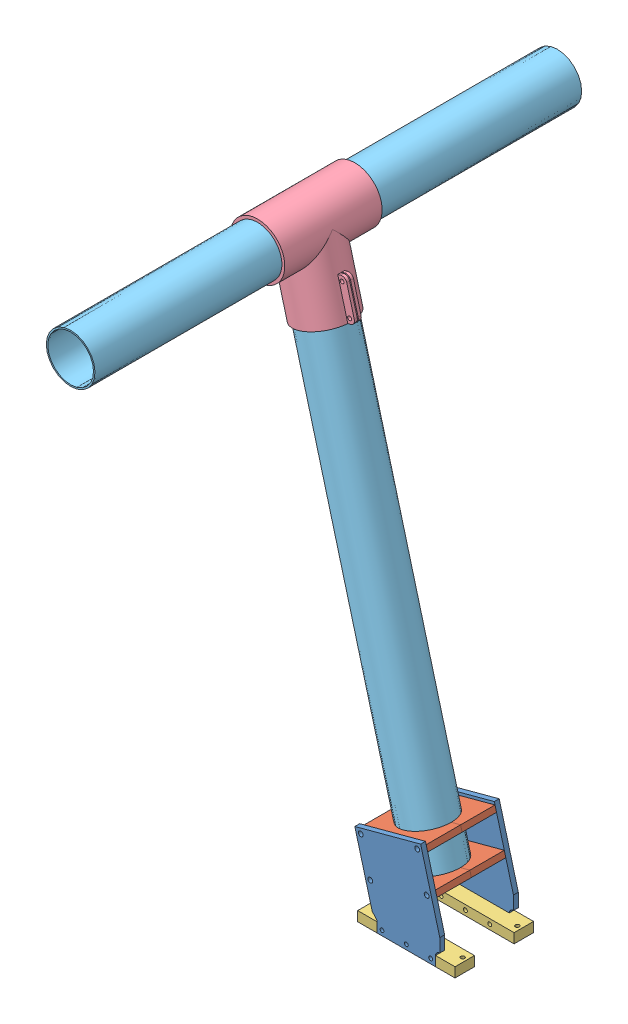
SolidWorks assembly DroneLegAssembly, configuration Default. Lengths in mm.
Overall size (228.54 591.89 500).
11 component instances, 5 part files, 25 mates.
Components (placement in the parent):
- DroneLegHolder-1: DroneLegHolder [Default] at (24.5531 1.0156 69.8023) size (87.27 101.47 5)
- 50mmTubeClamp-1: 50mmTubeClamp [Default] at (47.7584 47.4978 110.1489) x (0.965926 0.258819 0) z (-0.258819 0.965926 0) size (70 35.35 6)
- 50mmTubeClamp-2: 50mmTubeClamp [Default] at (35.6425 92.7146 110.1489) x (-0.965926 -0.258819 0) z (0.258819 -0.965926 0) size (70 35.35 6)
- 50mmTubeClamp-3: 50mmTubeClamp [Default] at (35.6425 92.7146 110.1489) x (0.965926 0.258819 0) z (0.258819 -0.965926 0) size (70 35.35 6)
- 50mmTubeClamp-4: 50mmTubeClamp [Default] at (45.1702 57.157 110.1489) x (0.965926 0.258819 0) z (0.258819 -0.965926 0) size (70 35.35 6)
- DroneLegHolder-2: DroneLegHolder [Default] at (24.5531 1.0156 145.4956) size (87.27 101.47 5)
- 50mmDroneLegToBase-1: 50mmDroneLegToBase [Default] at (47.7381 1.0156 73.7515) x (0 0 1) z (-1 0 0) size (20 10 100)
- 50mmDroneLegToBase-2: 50mmDroneLegToBase [Default] at (61.3681 1.0156 146.5463) x (0 0 -1) z (1 0 0) size (20 10 100)
- New50mmBottomJoint-1: New50mmBottomJoint [Default] at (-88.6393 556.5407 160.1489) x (0.965926 0.258819 0) z (0 0 -1) size (64 103 100)
- Short50mmDroneLeg-1: Short50mmDroneLeg [Default] at (47.2407 49.4296 110.1489) x (0.779439 0.20885 -0.590641) z (-0.258819 0.965926 0) size (50 50 500)
- Short50mmDroneLeg-2: Short50mmDroneLeg [Default] at (-88.6393 556.5407 -147.8451) x (0.716049 -0.69805 0) z (0 0 1) size (50 50 500)
Mates (geometry in assembly coordinates):
- Coincident1: coincident anti-aligned: plane of 50mmTubeClamp-2 through (4.4233 73.9967 110.1489) normal (0 0 1); plane of 50mmTubeClamp-3 through (72.0381 92.1141 110.1489) normal (0 0 -1)
- Coincident3: coincident anti-aligned: plane of 50mmTubeClamp-1 through (21.022 50.6865 110.1489) normal (0 0 1); plane of 50mmTubeClamp-4 through (23.6102 41.0273 110.1489) normal (0 0 -1)
- Coincident5: coincident anti-aligned: plane of 50mmTubeClamp-4 through (81.5658 56.5564 145.4956) normal (0 0 1); plane of DroneLegHolder-2 through (88.9139 11.0156 145.4956) normal (0 0 -1)
- Coincident6: coincident anti-aligned: plane of DroneLegHolder-2 through (88.9139 11.0156 145.4956) normal (0 0 -1); plane of 50mmDroneLegToBase-2 through (84.5531 11.0156 145.4956) normal (0 0 1)
- Coincident9: coincident anti-aligned: plane of DroneLegHolder-2 through (24.5531 11.0156 155.4956) normal (-1 0 0); plane of 50mmDroneLegToBase-2 through (24.5531 11.0156 155.4956) normal (1 0 0)
- Concentric13: concentric anti-aligned: cylinder of DroneLegHolder-2 through (29.5531 6.0156 155.4956) axis (0 0 -1) radius 2; cylinder of 50mmDroneLegToBase-2 through (29.5531 6.0156 115.4956) axis (0 0 1) radius 2
- Concentric14: concentric aligned: cylinder of DroneLegHolder-1 through (29.5531 6.0156 79.8023) axis (0 0 -1) radius 2; cylinder of 50mmDroneLegToBase-1 through (29.5531 6.0156 104.8023) axis (0 0 -1) radius 2
- Concentric41: concentric anti-aligned: cylinder of 50mmTubeClamp-2 through (38.2307 83.0554 110.1489) axis (-0.258819 0.965926 0) radius 25; cylinder of Short50mmDroneLeg-1 through (-82.1688 532.3925 110.1489) axis (0.258819 -0.965926 0) radius 25
- Concentric42: concentric anti-aligned: cylinder of New50mmBottomJoint-1 through (-69.2278 484.0962 110.1489) axis (-0.258819 0.965926 0) radius 25; cylinder of Short50mmDroneLeg-1 through (-82.1688 532.3925 110.1489) axis (0.258819 -0.965926 0) radius 25
- Concentric43: concentric anti-aligned: cylinder of New50mmBottomJoint-1 through (-88.6393 556.5407 60.1489) axis (0 0 1) radius 25; cylinder of Short50mmDroneLeg-2 through (-88.6393 556.5407 352.1549) axis (0 0 -1) radius 25
- Concentric44: concentric anti-aligned: cylinder of 50mmTubeClamp-2 through (7.9589 80.1204 48.1489) axis (0 0 1) radius 1.325; cylinder of 50mmTubeClamp-3 through (7.9589 80.1204 172.1489) axis (0 0 -1) radius 1.325
- Concentric45: concentric anti-aligned: cylinder of 50mmTubeClamp-4 through (47.7584 47.4978 110.1489) axis (-0.258819 0.965926 0) radius 25; cylinder of Short50mmDroneLeg-1 through (-82.1688 532.3925 110.1489) axis (0.258819 -0.965926 0) radius 25
- Concentric46: concentric anti-aligned: cylinder of 50mmTubeClamp-1 through (17.4865 44.5628 48.1489) axis (0 0 1) radius 1.325; cylinder of 50mmTubeClamp-4 through (17.4865 44.5628 172.1489) axis (0 0 -1) radius 1.325
- Coincident10: coincident aligned: plane of DroneLegHolder-1 through (24.5531 1.0156 79.8023) normal (0 -1 0); plane of 50mmDroneLegToBase-1 through (47.7381 1.0156 73.7515) normal (0 -1 0)
- Coincident11: coincident anti-aligned: plane of DroneLegHolder-1 through (88.9139 11.0156 74.8023) normal (0 0 1); plane of 50mmDroneLegToBase-1 through (24.5531 11.0156 74.8023) normal (0 0 -1)
- Coincident12: coincident anti-aligned: plane of DroneLegHolder-1 through (88.9139 11.0156 74.8023) normal (0 0 1); plane of 50mmTubeClamp-1 through (78.9776 66.2157 74.8023) normal (0 0 -1)
- Concentric47: concentric aligned: cylinder of 50mmTubeClamp-4 through (75.442 60.092 172.1489) axis (0 0 -1) radius 1.325; cylinder of DroneLegHolder-2 through (75.442 60.092 155.4956) axis (0 0 -1) radius 2.5
- Concentric48: concentric anti-aligned: cylinder of DroneLegHolder-1 through (75.442 60.092 79.8023) axis (0 0 -1) radius 2.5; cylinder of 50mmTubeClamp-1 through (75.442 60.092 48.1489) axis (0 0 1) radius 1.325
- Coincident13: coincident aligned: plane of 50mmTubeClamp-1 through (47.2407 49.4296 110.1489) normal (0.258819 -0.965926 0); plane of 50mmTubeClamp-4 through (47.2407 49.4296 110.1489) normal (0.258819 -0.965926 0)
- Coincident14: coincident aligned: line of 50mmTubeClamp-2 through (71.5205 94.0459 74.8023) axis (0 0 1); line of 50mmTubeClamp-3 through (71.5205 94.0459 110.1489) axis (0 0 1)
- Coincident15: coincident aligned: plane of 50mmTubeClamp-4 through (47.2407 49.4296 110.1489) normal (0.258819 -0.965926 0); plane of Short50mmDroneLeg-1 through (47.2407 49.4296 110.1489) normal (0.258819 -0.965926 0)
- Coincident16: coincident aligned: plane of 50mmTubeClamp-4 through (81.5658 56.5564 110.1489) normal (0.965926 0.258819 0); plane of DroneLegHolder-2 through (88.9139 29.133 155.4956) normal (0.965926 0.258819 0)
- Coincident17: coincident aligned: plane of DroneLegHolder-1 through (88.9139 29.133 79.8023) normal (0.965926 0.258819 0); plane of 50mmTubeClamp-1 through (78.9776 66.2157 110.1489) normal (0.965926 0.258819 0)
- Tangent1: tangent anti-aligned: plane of Short50mmDroneLeg-1 through (-82.1688 532.3925 110.1489) normal (-0.258819 0.965926 0); cylinder of Short50mmDroneLeg-2 through (-88.6393 556.5407 352.1549) axis (0 0 -1) radius 25
- Parallel1: parallel aligned: plane of DroneLegHolder-1 through (88.9139 11.0156 69.8023) normal (0 0 -1); plane of Short50mmDroneLeg-2 through (-88.6393 556.5407 -147.8451) normal (0 0 -1)
